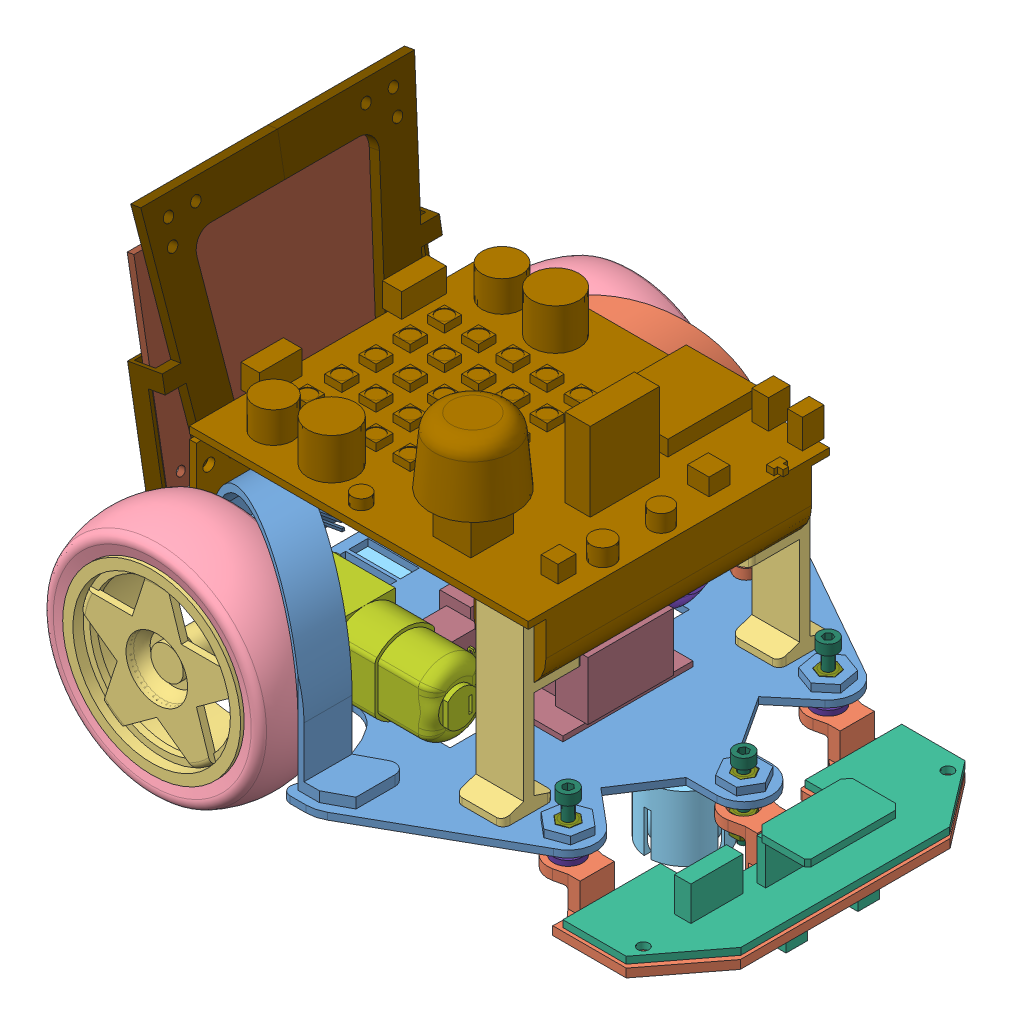
SolidWorks assembly BitMovelSeguidor_passoApasso, configuration Valor predeterminado. Lengths in mm.
Overall size (200.15 122.3 148.4).
46 component instances, 25 part files, 94 mates.
Components (placement in the parent):
- chassis_com_ajuste_m3-3: chassis_com_ajuste_m3 [Valor predeterminado] at origin size (130.17 20 141)
- suporte_sensores_com_ajuste_m3-3: suporte_sensores_com_ajuste_m3 [Valor predeterminado] at (138.3 -14.75 0) size (49 11.25 99)
- roda-1: roda [Valor predeterminado] at (16.43 13.18 70.62) x (0 0 -1) z (1 0 0) size (32 68 68)
  - aro-2: aro [Valor predeterminado] at origin size (32 52 52)
  - pneu-2: pneu [Valor predeterminado] at (-0.45 0 0) size (23.96 68 68)
- roda-2: roda [Valor predeterminado] at (16.43 13.18 -70.62) x (0 0 1) z (-1 0 0) size (32 68 68)
  - aro-2: aro [Valor predeterminado] at origin size (32 52 52)
  - pneu-2: pneu [Valor predeterminado] at (-0.45 0 0) size (23.96 68 68)
- esfera_apoio-1: esfera_apoio [Valor predeterminado] at (101.5 -23.8225 0) size (21.6 21.67 21.6)
- Placa_sensores_reflexivos-1: Placa_sensores_reflexivos [Valor predeterminado] at (132 -12.5 0) x (0 0 1) z (-1 0 0) size (99 26 34.88)
- motor_redutor-1: motor_redutor [Valor predeterminado] at (35 13.25 34.5) x (0 0 -1) z (1 0 0) size (36.88 22.5 65.85)
- esq_motor_redutor-2: esq_motor_redutor [Valor predeterminado] at (35 13.25 -34.5) x (0 0 1) z (-1 0 0) size (36.88 22.5 65.85)
- placa_BitDogLab-1: placa_BitDogLab [Valor predeterminado] at (50.3609 52.4 0) x (0 0 -1) z (1 0 0) size (89.54 57.4 101.27)
- Placa_expansor_I2C_v2-1: Placa_expansor_I2C_v2 [Valor predeterminado] at (-3.9802 16.8143 0) x (0 0 1) z (-0.173648 0.984808 0) size (32.5 13.5 19.5)
- Placa_monitoramento_corrente-1: Placa_monitoramento_corrente [Valor predeterminado] at (-15.88 55.8408 0) x (0 0 -1) z (-0.173648 0.984808 0) size (77 6 57.5)
- parafusoMotor-1: parafusoMotor [Valor predeterminado] at (36.3 4.34 45) x (0 0 -1) z (1 0 0) size (30 5 5)
- parafusoMotor-2: parafusoMotor [Valor predeterminado] at (36.3 4.34 -44.8) x (0 0 1) z (-1 0 0) size (30 5 5)
- Placa_MotorDriver-1: Placa_MotorDriver [Valor predeterminado] at (62 4 0) size (50.8 18.5 38)
- Placa_modulo_bluetooth-2: Placa_modulo_bluetooth [Valor predeterminado] at (-33.4211 50.2234 -23.2114) x (0.984808 0.173648 0) z (0 0 1) size (32.5 2 19.5)
- M3_assembly_push-4: M3_assembly_push [Valor predeterminado] at (105.5 12.4 38) x (0.939693 0 -0.34202) z (0.34202 0 0.939693) size (8.5 23 8.5)
  - M3_cap_screw-1: M3_cap_screw [Valor predeterminado] at origin size (5.5 23 5.5)
  - M3_nut-1: M3_nut [Valor predeterminado] at (0 -10.4 0) size (6.35 3.17 5.5)
  - M3_nut-2: M3_nut [Valor predeterminado] at (0 -19.55 0) size (6.35 3.17 5.5)
  - M3_nut-3: M3_nut [Valor predeterminado] at (0 -15.65 0) size (6.35 3.17 5.5)
  - arruela_m3-1: arruela_m3 [Valor predeterminado] at (0 -17.15 0) size (8.5 1.5 8.5)
- M3_assembly-4: M3_assembly [Valor predeterminado] at (118.84 9.2 0) size (8.5 23 8.5)
  - M3_cap_screw-1: M3_cap_screw [Valor predeterminado] at origin size (5.5 23 5.5)
  - M3_nut-1: M3_nut [Valor predeterminado] at (0 -7.4 0) size (6.35 3.17 5.5)
  - M3_nut-2: M3_nut [Valor predeterminado] at (0 -20.9 0) size (6.35 3.17 5.5)
  - M3_nut-3: M3_nut [Valor predeterminado] at (0 -17 0) size (6.35 3.17 5.5)
  - arruela_m3-1: arruela_m3 [Valor predeterminado] at (0 -18.5 0) size (8.5 1.5 8.5)
- M3_assembly_push-3: M3_assembly_push [Valor predeterminado] at (105.5 12.4 -38) x (0.939693 0 0.34202) z (-0.34202 0 0.939693) size (8.5 23 8.5)
  - M3_cap_screw-1: M3_cap_screw [Valor predeterminado] at origin size (5.5 23 5.5)
  - M3_nut-1: M3_nut [Valor predeterminado] at (0 -10.4 0) size (6.35 3.17 5.5)
  - M3_nut-2: M3_nut [Valor predeterminado] at (0 -19.55 0) size (6.35 3.17 5.5)
  - M3_nut-3: M3_nut [Valor predeterminado] at (0 -15.65 0) size (6.35 3.17 5.5)
  - arruela_m3-1: arruela_m3 [Valor predeterminado] at (0 -17.15 0) size (8.5 1.5 8.5)
- Aerofolio-1: Aerofolio [Default] at (-17.2221 83.2745 -40) x (0 0 1) z (-0.984808 -0.173648 0) size (80 29.29 79.07) (hidden)
- Suporte_Aerofolio2-1: Suporte_Aerofolio2 [Valor predeterminado] at (-11.6344 65.9821 0) x (0 0 -1) z (0.984808 0.173648 0) size (80 100 10.94) (hidden)
- Suporte_Aerofolio3-1: Suporte_Aerofolio3 [Valor predeterminado] at (-2.9544 -0.5209 0) x (0 0 -1) z (0.984808 0.173648 0) size (81 100 10.3)
- paralama-1: paralama [Valor predeterminado] at (29.5701 19.9 53.6334) x (0.882948 0 0.469472) z (-0.469472 0 0.882948) size (79.74 50.4 22.99)
- paralama_esquerdo_v2-2: paralama_esquerdo_v2 [Valor predeterminado] at (29.5701 19.9 -53.6334) x (0.882948 0 -0.469472) z (0.469472 0 0.882948) size (79.74 50.4 22.99)
- suporte_frontal_BitDog-1: suporte_frontal_BitDog [Valor predeterminado] at (89.3609 2 40.33) x (0 0 -1) z (1 0 0) size (23 50.4 14)
- suporte_frontal_BitDog-2: suporte_frontal_BitDog [Valor predeterminado] at (89.3609 2 -40.33) x (0 0 1) z (-1 0 0) size (23 50.4 14)
- suporte_adaptador_i2c-1: suporte_adaptador_i2c [Valor predeterminado] at (-5.7529 15.35 0) x (0 0 1) z (-0.173648 0.984808 0) size (36.5 2 19.5)
- bateria_motor-1: bateria_motor [Valor predeterminado] at (45 -5 0) x (0 0 -1) z (1 0 0) size (25 10 90)
Mates (geometry in assembly coordinates):
- Distância4: distance = 124 mm aligned: plane of chassis-2 through (0.4379 0.5122 -124) normal (0 0 1)
- Distância5: distance = 124 mm aligned: plane of chassis-4 through (163.4129 -1.1812 -124) normal (0 0 1)
- Coincidente13: coincident aligned: plane of chassis-4 through (163.4129 -1.1812 -124) normal (0 0 1); plane of suporte_sensores_avulsos-2 through (288.424 -15.4312 -124) normal (0 0 1)
- Distância7: distance = 1 mm anti-aligned: plane of sensor_individual-13 through (266.733 0.5149 -102) normal (0 0 -1); plane of chassis-4 through (279.4129 0.8188 -103) normal (0 0 1)
- Coincidente18: coincident aligned: plane of suporte_sensores_com_ajuste_m3-3 through (138.3 -14.75 0) normal (0 0 1)
- Distância18: distance = 1 mm anti-aligned: plane of sensor_individual-9 through (135.4345 -11.5 16.3209) normal (0 -1 0); plane of suporte_sensores_com_ajuste_m3-3 through (138.3 -13.5 0) normal (0 1 0)
- Coincidente38: coincident aligned: plane of esfera_apoio-1 through (101.5 -23.8225 0) normal (0 0 1)
- Coincidente43: coincident anti-aligned: plane of parafuso_ajuste_10mm-1 through (102.8368 -11.3 38) normal (0 1 0); plane of anel_trava_ajuste-5 through (102.8368 -11.3 38) normal (0 -1 0)
- Coincidente44: coincident anti-aligned: plane of parafuso_ajuste_10mm-1 through (102.8368 -16.3 38) normal (0 -1 0); plane of anel_trava_ajuste-6 through (102.8368 -16.3 38) normal (0 1 0)
- Coincidente45: coincident anti-aligned: plane of parafuso_ajuste_10mm-3 through (118.8368 -16.3 0) normal (0 -1 0); plane of anel_trava_ajuste-3 through (118.8368 -16.3 0) normal (0 1 0)
- Coincidente46: coincident anti-aligned: plane of parafuso_ajuste_10mm-3 through (118.8368 -11.3 0) normal (0 1 0); plane of anel_trava_ajuste-4 through (118.8368 -11.3 0) normal (0 -1 0)
- Coincidente47: coincident anti-aligned: plane of parafuso_ajuste_10mm-2 through (102.8368 -16.3 -38) normal (0 -1 0); plane of anel_trava_ajuste-1 through (102.8368 -16.3 -38) normal (0 1 0)
- Coincidente48: coincident anti-aligned: plane of parafuso_ajuste_10mm-2 through (102.8368 -11.3 -38) normal (0 1 0); plane of anel_trava_ajuste-2 through (102.8368 -11.3 -38) normal (0 -1 0)
- Concêntrico4: concentric aligned: cylinder of parafuso_ajuste_10mm-2 through (102.8368 -23.3903 -38) axis (0 -1 0) radius 0.8013; cylinder of anel_trava_ajuste-1 through (102.8368 -16.3 -38) axis (0 -1 0) radius 0.8
- Concêntrico5: concentric aligned: cylinder of parafuso_ajuste_10mm-2 through (102.8368 -23.3903 -38) axis (0 -1 0) radius 0.8013; cylinder of anel_trava_ajuste-2 through (102.8368 -10.55 -38) axis (0 -1 0) radius 0.8
- Concêntrico6: concentric aligned: cylinder of parafuso_ajuste_10mm-1 through (102.8368 -23.3903 38) axis (0 -1 0) radius 0.8013; cylinder of anel_trava_ajuste-6 through (102.8368 -16.3 38) axis (0 -1 0) radius 0.8
- Concêntrico7: concentric aligned: cylinder of parafuso_ajuste_10mm-1 through (102.8368 -23.3903 38) axis (0 -1 0) radius 0.8013; cylinder of anel_trava_ajuste-5 through (102.8368 -10.55 38) axis (0 -1 0) radius 0.8
- Concêntrico8: concentric aligned: cylinder of parafuso_ajuste_10mm-3 through (118.8368 -23.3903 0) axis (0 -1 0) radius 0.8013; cylinder of anel_trava_ajuste-3 through (118.8368 -16.3 0) axis (0 -1 0) radius 0.8
- Concêntrico9: concentric aligned: cylinder of parafuso_ajuste_10mm-3 through (118.8368 -23.3903 0) axis (0 -1 0) radius 0.8013; cylinder of anel_trava_ajuste-4 through (118.8368 -10.55 0) axis (0 -1 0) radius 0.8
- Concêntrico12: concentric: cylinder of chassis_com_ajuste-3 through (102.8015 4.5 38.0405) axis (0 -1 0) radius 6; cylinder of parafuso_ajuste_10mm-1 through (102.8368 -23.3903 38) axis (0 -1 0) radius 1.6025
- Coincidente50: coincident aligned: plane of chassis_com_ajuste_m3-3 through (0 0 0) normal (0 0 1)
- Coincidente51: coincident aligned: plane of chassis_com_ajuste_m3-3 through (0 0 0) normal (0 1 0)
- Coincidente52: coincident aligned: plane of chassis_com_ajuste_m3-3 through (0 0 0) normal (1 0 0)
- Ângulo1: planar angle = 5.585054 rad aligned: plane of parafuso_ajuste_10mm-1 through (102.8368 15 38) normal (0.642788 0 0.766044)
- Ângulo2: planar angle = 5.585054 rad aligned: plane of parafuso_ajuste_10mm-3 through (118.8368 15 0) normal (-0.642788 0 0.766044)
- Coincidente58: coincident aligned: plane of Placa_sensores_reflexivos-1 through (132 -12.5 0) normal (0 0 1)
- Coincidente62: coincident anti-aligned: plane of chassis_com_ajuste_m3-3 through (10.4471 17.5086 25) normal (0 0 1); plane of motor_redutor-1 through (9 20.5 25) normal (0 0 -1)
- Coincidente63: coincident anti-aligned: plane of chassis_com_ajuste_m3-3 through (105.5 2 38) normal (0 1 0); plane of motor_redutor-1 through (53.5 2 25) normal (0 -1 0)
- Coincidente67: coincident anti-aligned: plane of placa_BitDogLab-1 through (50.3609 52.4 0) normal (0 0 -1)
- Concêntrico13: concentric anti-aligned: cylinder of roda-1/aro-2 through (16.43 13.18 35.2504) axis (0 0 1) radius 4.75; cylinder of motor_redutor-1 through (16.43 13.18 52.94) axis (0 0 -1) radius 2.72
- Distância36: distance = 21.62 mm aligned: plane of roda-1/aro-2 through (16.43 36.18 46.62) normal (0 0 -1); plane of motor_redutor-1 through (9 20.5 25) normal (0 0 -1)
- Paralelo1: parallel aligned: plane of roda-1 through (16.43 13.18 70.62) normal (1 0 0)
- Coincidente70: coincident anti-aligned: plane of roda-1 through (16.43 13.18 70.62) normal (1 0 0); plane of roda-2 through (16.43 13.18 -70.62) normal (-1 0 0)
- Coincidente71: coincident aligned: plane of roda-1 through (16.43 13.18 70.62) normal (0 1 0); plane of roda-2 through (16.43 13.18 -70.62) normal (0 1 0)
- Simétrico1: symmetric aligned: plane of roda-1 through (16.43 13.18 70.62) normal (0 0 -1); plane of roda-2 through (16.43 13.18 -70.62) normal (0 0 1)
- Coincidente74: coincident anti-aligned: plane of Placa_monitoramento_corrente-1 through (-15.88 55.8408 0) normal (0 0 -1)
- Concêntrico14: concentric anti-aligned: cylinder of motor_redutor-1 through (36.3 4.34 16.06) axis (0 0 1) radius 1.5; cylinder of parafusoMotor-1 through (36.3 4.34 45) axis (0 0 -1) radius 1.25
- Concêntrico15: concentric anti-aligned: cylinder of esq_motor_redutor-2 through (36.3 4.34 -16.06) axis (0 0 -1) radius 1.5; cylinder of parafusoMotor-2 through (36.3 4.34 -44.8) axis (0 0 1) radius 1.25
- Distância37: distance = 1 mm aligned: plane of parafusoMotor-1 through (34.117 4.34 45) normal (0 0 1); plane of motor_redutor-1 through (9 20.5 44) normal (0 0 1)
- Distância38: distance = 0.8 mm aligned: plane of parafusoMotor-2 through (38.483 4.34 -44.8) normal (0 0 -1); plane of esq_motor_redutor-2 through (9 20.5 -44) normal (0 0 -1)
- Paralelo2: parallel anti-aligned: plane of parafusoMotor-2 through (36.3 4.34 -44.8) normal (-1 0 0)
- Paralelo3: parallel aligned: plane of parafusoMotor-1 through (36.3 4.34 45) normal (1 0 0)
- Distância39: distance = 5 mm aligned: plane of motor_redutor-1 through (5 20.5 25) normal (-1 0 0); plane of chassis_com_ajuste_m3-3 through (0 2 -38) normal (-1 0 0)
- Distância40: distance = 2 mm anti-aligned: plane of Placa_MotorDriver-1 through (62 4 0) normal (0 -1 0); plane of chassis_com_ajuste_m3-3 through (105.5 2 38) normal (0 1 0)
- Concêntrico16: concentric aligned: cylinder of chassis_com_ajuste_m3-3 through (69 9 -15.3) axis (0 -1 0) radius 1.25; cylinder of Placa_MotorDriver-1 through (69 5.5 -15.3) axis (0 -1 0) radius 2
- Distância41: distance = 2 mm anti-aligned: plane of Placa_monitoramento_corrente-1 through (-17.8496 55.4935 0) normal (-0.984808 -0.173648 0); plane of Suporte_Aerofolio2-1 through (-16.2161 34.7115 40) normal (0.984808 0.173648 0)
- Coincidente88: coincident anti-aligned: plane of Placa_monitoramento_corrente-2 through (-42.044 72.0117 0) normal (0 0 -1)
- Coincidente89: coincident anti-aligned: plane of Placa_monitoramento_corrente-1 through (-17.8496 55.4935 0) normal (-0.984808 -0.173648 0); plane of Placa_expansor_I2C-2 through (-17.7652 55.0148 -13.4614) normal (0.984808 0.173648 0)
- Concêntrico17: concentric anti-aligned: cylinder of chassis_com_ajuste_m3-3 through (105.5 2 38) axis (0 -1 0) radius 1.75; cylinder of M3_assembly_push-4/M3_cap_screw-1 through (105.5 -10.6 38) axis (0 1 0) radius 1.5
- Concêntrico19: concentric anti-aligned: cylinder of chassis_com_ajuste_m3-3 through (105.5 2 -38) axis (0 -1 0) radius 1.75; cylinder of M3_assembly_push-3/M3_cap_screw-1 through (105.5 -10.6 -38) axis (0 1 0) radius 1.5
- Coincidente90: coincident anti-aligned: plane of chassis_com_ajuste_m3-3 through (105.5 2 38) normal (0 1 0); plane of M3_assembly_push-4/M3_nut-1 through (105.5 2 38) normal (0 -1 0)
- Coincidente93: coincident anti-aligned: plane of Suporte_Aerofolio2-1 through (-14.0964 65.548 0) normal (-0.984808 -0.173648 0); plane of Aerofolio-1 through (-18.5245 90.6606 40) normal (0.984808 0.173648 0)
- Coincidente95: coincident anti-aligned: plane of assembly through (0 0 0) normal (0 0 1); plane of Aerofolio-1 through (-17.2221 83.2745 0) normal (0 0 -1)
- Coincidente96: coincident anti-aligned: plane of chassis_com_ajuste_m3-3 through (0 0 45.7777) normal (-0.984808 -0.173648 0); plane of Suporte_Aerofolio2-1 through (-11.6344 65.9821 0) normal (0.984808 0.173648 0)
- Coincidente97: coincident: line of Aerofolio-1 through (-19.8268 98.0467 40) axis (0 0 -1); plane of Suporte_Aerofolio2-1 through (-17.3648 98.4808 40) normal (-0.173648 0.984808 0)
- Coincidente98: coincident anti-aligned: plane of Suporte_Aerofolio2-1 through (-11.6344 65.9821 0) normal (0 0 -1)
- Coincidente99: coincident: plane of chassis_com_ajuste_m3-3 through (105.5 0 38) normal (0 -1 0); line of Suporte_Aerofolio2-1 through (0 0 9) axis (0 0 1)
- Coincidente100: coincident: plane of chassis_com_ajuste_m3-3 through (0 0 45.7777) normal (-0.984808 -0.173648 0); plane of Suporte_Aerofolio3-1 through (0 0 39.0994) normal (0.984808 0.173648 0)
- Coincidente101: coincident: line of chassis_com_ajuste_m3-3 through (0 0 27.5) axis (0 0 -1); line of Suporte_Aerofolio3-1 through (0 0 75.2662) axis (0 0 -1)
- Coincidente102: coincident anti-aligned: plane of Suporte_Aerofolio3-1 through (-2.9544 -0.5209 0) normal (0 0 -1)
- Coincidente103: coincident aligned: plane of suporte_sensores_com_ajuste_m3-3 through (148.5 -13.5 0) normal (1 0 0); plane of Placa_sensores_reflexivos-1 through (148.5 -10.5 30.5) normal (1 0 0)
- Concêntrico22: concentric aligned: cylinder of suporte_sensores_com_ajuste_m3-3 through (105.5 -7.75 38) axis (0 1 0) radius 3.75; cylinder of M3_assembly_push-4/M3_cap_screw-1 through (105.5 -10.6 38) axis (0 1 0) radius 1.5
- Coincidente104: coincident aligned: plane of M3_assembly_push-4 through (105.5 12.4 38) normal (0 1 0); plane of M3_assembly_push-3 through (105.5 12.4 -38) normal (0 1 0)
- Coincidente106: coincident aligned: plane of M3_assembly-4/M3_nut-1 through (118.84 4.2 0) normal (0 1 0); plane of chassis_com_ajuste_m3-3 through (0 4.2 0) normal (0 1 0)
- Distância43: distance = 2 mm anti-aligned: plane of Placa_expansor_I2C_v2-1 through (-3.7037 26.7635 -16.25) normal (-0.173648 0.984808 0); plane of Placa_monitoramento_corrente-1 through (-12.8573 27.1803 38.5) normal (0.173648 -0.984808 0)
- Coincidente110: coincident aligned: plane of Placa_expansor_I2C_v2-1 through (-3.9802 16.8143 0) normal (0 0 1)
- Distância42: distance = 3 mm anti-aligned: plane of Placa_monitoramento_corrente-1 through (-12.8573 27.1803 38.5) normal (0.173648 -0.984808 0); plane of Suporte_Aerofolio3-1 through (-7.4693 25.0841 0) normal (-0.173648 0.984808 0)
- Coincidente112: coincident: line of chassis_com_ajuste_m3-3 through (0 0 27.5) axis (0 0 -1); plane of Suporte_Aerofolio3-1 through (0 0 0) normal (0.173648 -0.984808 0)
- Coincidente113: coincident anti-aligned: plane of chassis_com_ajuste_m3-3 through (0 0 45.7777) normal (-0.984808 -0.173648 0); plane of Suporte_Aerofolio3-1 through (0 0 0) normal (0.984808 0.173648 0)
- Distância46: distance = 56.5 mm aligned: plane of paralama-1 through (56.5 19.9 67.9523) normal (-1 0 0); plane of chassis_com_ajuste_m3-3 through (0 2 -38) normal (-1 0 0)
- Coincidente118: coincident anti-aligned: plane of placa_BitDogLab-1 through (0.8609 28 -44) normal (0 -1 0); plane of paralama-1 through (0.1679 28 38) normal (0 1 0)
- Coincidente119: coincident anti-aligned: plane of chassis_com_ajuste_m3-3 through (105.5 2 38) normal (0 1 0); plane of paralama-1 through (69.7442 2 74.9944) normal (0 -1 0)
- Coincidente121: coincident anti-aligned: plane of placa_BitDogLab-1 through (2.8609 51 -44) normal (1 0 0); plane of paralama-1 through (2.8609 28 39.4319) normal (-1 0 0)
- Tangente1: tangent anti-aligned: plane of chassis_com_ajuste_m3-3 through (0 2 38) normal (0 0 1); cylinder of paralama-1 through (73.0429 2 142.6943) axis (-1 0 0) radius 104.6943
- Coincidente123: coincident anti-aligned: plane of chassis_com_ajuste_m3-3 through (105.5 2 38) normal (0 1 0); plane of suporte_frontal_BitDog-1 through (96.3609 2 40.33) normal (0 -1 0)
- Distância48: distance = 5 mm: plane of suporte_frontal_BitDog-2 through (94.8609 2 -44.5) normal (1 0 0); plane of placa_BitDogLab-1 through (99.8609 54.4 44) normal (1 0 0)
- Coincidente127: coincident anti-aligned: plane of chassis_com_ajuste_m3-3 through (105.5 2 38) normal (0 1 0); plane of suporte_frontal_BitDog-2 through (82.3609 2 -40.33) normal (0 -1 0)
- Coincidente128: coincident anti-aligned: plane of placa_BitDogLab-1 through (0.8609 54.4 44) normal (0 0 1); plane of suporte_frontal_BitDog-1
- Coincidente129: coincident: plane of placa_BitDogLab-1 through (0.8609 54.4 -44) normal (0 0 -1); plane of suporte_frontal_BitDog-2 through (93.2707 2 -44) normal (0 0 1)
- Coincidente130: coincident: plane of placa_BitDogLab-1 through (0.8609 54.4 44) normal (0 0 1); plane of suporte_frontal_BitDog-1 through (96.7709 2 44) normal (0 0 -1)
- Concêntrico23: concentric aligned: cylinder of placa_BitDogLab-1 through (89.3609 42.4 -38.83) axis (0 0 1) radius 10.5; cylinder of suporte_frontal_BitDog-1 through (89.3609 42.4 24.83) axis (0 0 1) radius 10.5
- Coincidente131: coincident anti-aligned: plane of placa_BitDogLab-1 through (89.3609 42.4 38.83) normal (0 0 1); plane of suporte_frontal_BitDog-1 through (96.3609 2 38.83) normal (0 0 -1)
- Coincidente132: coincident anti-aligned: plane of placa_BitDogLab-1 through (89.3609 42.4 -38.83) normal (0 0 -1); plane of suporte_frontal_BitDog-2 through (82.3609 2 -38.83) normal (0 0 1)
- Concêntrico24: concentric anti-aligned: cylinder of placa_BitDogLab-1 through (89.3609 42.4 -38.83) axis (0 0 1) radius 10.5; cylinder of suporte_frontal_BitDog-2 through (89.3609 42.4 -24.83) axis (0 0 -1) radius 10.5
- Coincidente134: coincident anti-aligned: plane of Placa_expansor_I2C_v2-1 through (-3.9802 16.8143 0) normal (-0.984808 -0.173648 0); plane of suporte_adaptador_i2c-1 through (-3.7833 15.6973 0) normal (0.984808 0.173648 0)
- Coincidente135: coincident aligned: plane of suporte_adaptador_i2c-1 through (-5.7529 15.35 0) normal (0 0 1)
- Coincidente136: coincident aligned: plane of Suporte_Aerofolio3-1 through (-2.9544 -0.5209 0) normal (-0.984808 -0.173648 0); plane of suporte_adaptador_i2c-1 through (-5.7529 15.35 0) normal (-0.984808 -0.173648 0)
- Coincidente137: coincident anti-aligned: plane of chassis_com_ajuste_m3-3 through (105.5 0 38) normal (0 -1 0); plane of bateria_motor-1 through (90 0 7.5) normal (0 1 0)
- Coincidente138: coincident anti-aligned: plane of bateria_motor-1 through (45 -5 0) normal (0 0 -1)
- Coincidente139: coincident aligned: plane of chassis_com_ajuste_m3-3 through (0 2 -38) normal (-1 0 0); plane of bateria_motor-1 through (0 -5 7.5) normal (-1 0 0)
- Coincidente140: coincident anti-aligned: plane of suporte_sensores_com_ajuste_m3-3 through (138.3 -4.75 0) normal (0 1 0); plane of M3_assembly_push-4/arruela_m3-1 through (105.5 -4.75 38) normal (0 -1 0)
- Paralelo4: parallel anti-aligned: plane of chassis_com_ajuste_m3-3 through (104.9366 4.2 41.1954) normal (-0.34202 0 -0.939693); plane of M3_assembly_push-4/M3_nut-1 through (104.9486 4.4 41.1272) normal (0.34202 0 0.939693)
- Paralelo5: parallel anti-aligned: plane of chassis_com_ajuste_m3-3 through (106.0634 4.2 -34.8046) normal (-0.642788 0 -0.766044); plane of M3_assembly_push-3/M3_nut-1 through (106.0514 4.4 -34.8728) normal (0.642788 0 0.766044)
- Distância49: distance = 11.5 mm aligned: plane of esfera_apoio-1 through (101.5 -23.8225 0) normal (1 0 0); plane of bateria_motor-1 through (90 -5 7.5) normal (1 0 0)
